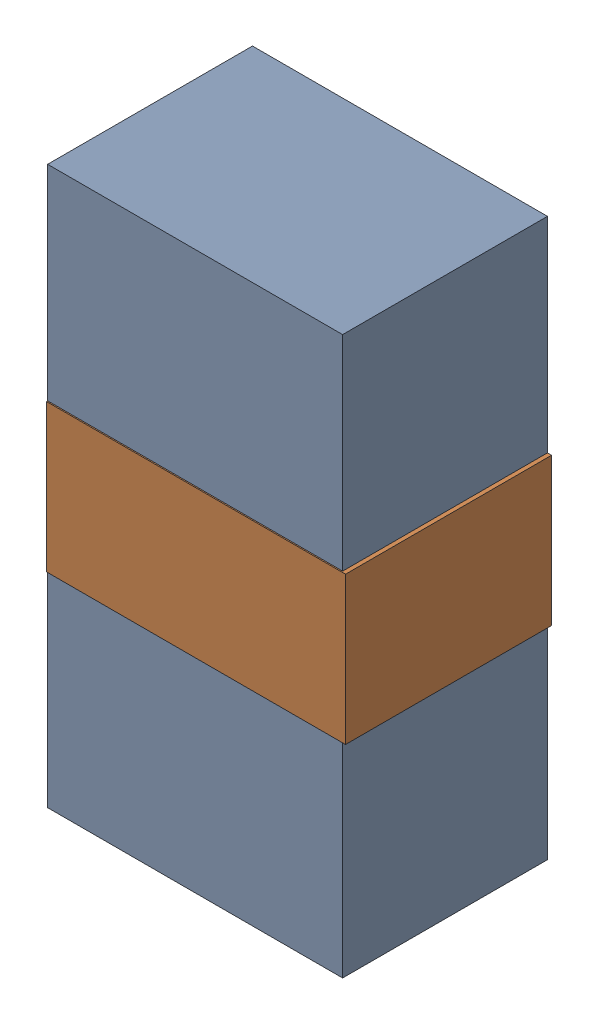
SolidWorks assembly LED2_Motor_7Kanaloa_v2.0.0_Motor, configuration Default. Lengths in mm.
Overall size (1.83 3.4 1.26).
4 component instances, 2 part files, 0 mates.
Components (placement in the parent):
- 334788016-1: 334788016 [Default] at (85.2675 145.288 0) size (1.8 3.4 1.25)
  - Extruded_12-1: Extruded_12 [Default] at origin size (1.8 3.4 1.25)
- 334787760-1: 334787760 [Default] at (85.28 145.288 0) size (1.83 0.9 1.26)
  - Extruded_13-1: Extruded_13 [Default] at origin size (1.83 0.9 1.26)
